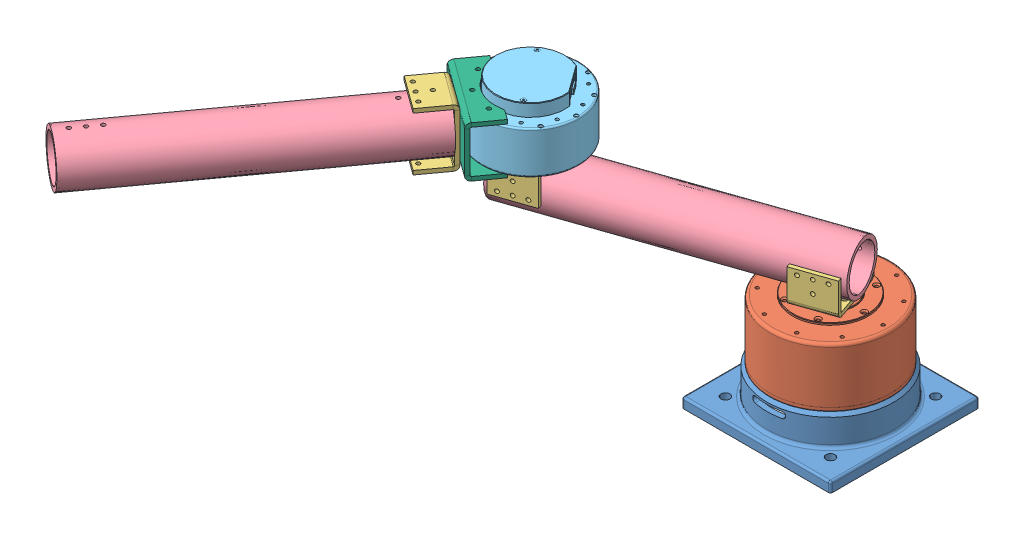
SolidWorks assembly Assembly_SCARA_P, configuration Default. Lengths in mm.
Overall size (523.57 217.6 447.44).
9 component instances, 6 part files, 25 mates.
Components (placement in the parent):
- base_link_X10-1: base_link_X10 [По умолчанию] at (81.3757 88.1097 90.3224) size (150 40 150)
- RMD-X10-S2-V3-1: RMD-X10-S2-V3 [По умолчанию] at (81.3757 180.7097 90.3224) x (0 0 -1) z (0 -1 0) size (122 122 74)
- corner_p_list__long_X10-1: corner_p_list__long_X10 [По умолчанию] at (100.7472 193.6097 83.6147) x (0.327206 0 0.944953) z (-0.944953 0 0.327206) size (58 34 41)
- tube-3: tube [По умолчанию] at (104.9995 218.6097 82.1423) x (-0.944953 0 0.327206) z (-0.327206 0 -0.944953) size (288 50 50)
- corner_p_list__long_X10-2: corner_p_list__long_X10 [По умолчанию] at (-124.1516 243.6097 161.4896) x (-0.327206 0 -0.944953) z (-0.944953 0 0.327206) size (58 34 41)
- corner_p_list__long_X10-3: corner_p_list__long_X10 [По умолчанию] at (-161.0459 271.1097 227.1652) x (0 -1 0) z (-0.808857 0 -0.588005) size (58 34 41)
- tube-4: tube [По умолчанию] at (-346.973 271.1097 448.0619) x (0.588005 0 -0.808857) z (0 -1 0) size (288 50 50)
- RMD-X8-S2-V3-1: RMD-X8-S2-V3 [По умолчанию] at (-143.5232 260.7097 168.1974) x (0.587565 0 0.809177) z (0 1 0) size (98 98 58.1)
- corner_p_list_X8-1: corner_p_list_X8 [По умолчанию] at (-205.2777 271.6097 185.12) x (0 -1 0) z (0.808857 0 0.588005) size (51 31 80)
Mates (geometry in assembly coordinates):
- Концентричный1: concentric anti-aligned: circle of First link-1; circle of RMD-X10-S2-V3-1
- Концентричный2: concentric anti-aligned: circle of First link-1; circle of RMD-X10-S2-V3-1
- Совпадение1: coincident anti-aligned: plane of First link-1 through (81.3757 128.1097 90.3224) normal (0 1 0); plane of RMD-X10-S2-V3-1 through (141.3757 128.1097 90.3224) normal (0 -1 0)
- Концентричный4: concentric anti-aligned: circle of RMD-X10-S2-V3-1; circle of corner_p_list__long_X10-1
- Совпадение3: coincident anti-aligned: plane of RMD-X10-S2-V3-1 through (81.3757 189.6097 90.3224) normal (0 1 0); plane of corner_p_list__long_X10-1 through (53.824 189.6097 73.4063) normal (0 -1 0)
- Концентричный5: concentric aligned: line of corner_p_list__long_X10-1 through (83.6986 218.6097 58.8287) axis (0.327206 0 0.944953); cylinder of tube-3 through (81.7354 218.6097 53.159) axis (0.327206 0 0.944953) radius 2
- Концентричный6: concentric aligned: cylinder of corner_p_list__long_X10-1 through (83.6986 218.6097 58.8287) axis (0.327206 0 0.944953) radius 2; cylinder of tube-3 through (81.7354 218.6097 53.159) axis (0.327206 0 0.944953) radius 2
- Концентричный7: concentric aligned: cylinder of corner_p_list__long_X10-1 through (71.8867 218.6097 62.9188) axis (0.327206 0 0.944953) radius 2; cylinder of tube-3 through (69.9235 218.6097 57.2491) axis (0.327206 0 0.944953) radius 2
- Касательность1: tangent anti-aligned: plane of corner_p_list__long_X10-1 through (70.1843 193.6097 120.654) normal (-0.327206 0 -0.944953); cylinder of tube-3 through (-167.147 218.6097 176.3775) axis (0.944953 0 -0.327206) radius 25
- Концентричный10: concentric anti-aligned: cylinder of tube-3 through (-166.7873 218.6097 139.2141) axis (0.327206 0 0.944953) radius 2; cylinder of corner_p_list__long_X10-2 through (-145.8461 218.6097 199.6911) axis (-0.327206 0 -0.944953) radius 2
- Концентричный11: concentric anti-aligned: cylinder of tube-3 through (-166.7873 218.6097 139.2141) axis (0.327206 0 0.944953) radius 2; cylinder of corner_p_list__long_X10-2 through (-145.8461 218.6097 199.6911) axis (-0.327206 0 -0.944953) radius 2
- Концентричный12: concentric anti-aligned: cylinder of tube-3 through (-154.9754 218.6097 135.124) axis (0.327206 0 0.944953) radius 2; cylinder of corner_p_list__long_X10-2 through (-134.0342 218.6097 195.601) axis (-0.327206 0 -0.944953) radius 2
- Касательность3: tangent anti-aligned: cylinder of tube-3 through (-167.147 218.6097 176.3775) axis (0.944953 0 -0.327206) radius 25; plane of corner_p_list__long_X10-2 through (-171.0749 243.6097 151.2812) normal (0.327206 0 0.944953)
- Концентричный24: concentric anti-aligned: cylinder of corner_p_list__long_X10-3 through (-184.9775 300.1097 225.2218) axis (0 -1 0) radius 2; cylinder of tube-4 through (-184.9775 236.1097 225.2218) axis (0 1 0) radius 2
- Концентричный25: concentric anti-aligned: cylinder of corner_p_list__long_X10-3 through (-184.9775 300.1097 225.2218) axis (0 -1 0) radius 2; cylinder of tube-4 through (-184.9775 236.1097 225.2218) axis (0 1 0) radius 2
- Концентричный26: concentric anti-aligned: cylinder of corner_p_list__long_X10-3 through (-192.3276 300.1097 235.3325) axis (0 -1 0) radius 2; cylinder of tube-4 through (-192.3276 236.1097 235.3325) axis (0 1 0) radius 2
- Касательность4: tangent anti-aligned: plane of corner_p_list__long_X10-3 through (-194.2091 296.1097 203.057) normal (0 -1 0); cylinder of tube-4 through (-177.6275 271.1097 215.1111) axis (-0.588005 0 0.808857) radius 25
- Концентричный27: concentric anti-aligned: circle of corner_p_list__long_X10-2; circle of RMD-X8-S2-V3-1
- Совпадение4: coincident anti-aligned: plane of corner_p_list__long_X10-2 through (-154.7146 247.6097 198.5289) normal (0 1 0); plane of RMD-X8-S2-V3-1 through (-143.5232 247.6097 168.1974) normal (0 -1 0)
- Концентричный30: concentric aligned: cylinder of RMD-X8-S2-V3-1 through (-143.5346 293.1097 210.1974) axis (0 1 0) radius 1.65; cylinder of corner_p_list_X8-1 through (-143.5346 246.1097 210.1974) axis (0 1 0) radius 2
- Концентричный31: concentric aligned: cylinder of RMD-X8-S2-V3-1 through (-168.2194 293.1097 202.1694) axis (0 1 0) radius 1.65; cylinder of corner_p_list_X8-1 through (-168.2194 246.1097 202.1694) axis (0 1 0) radius 2
- Совпадение6: coincident anti-aligned: plane of RMD-X8-S2-V3-1 through (-156.1558 293.1097 150.8001) normal (0 1 0); plane of corner_p_list_X8-1 through (-140.5692 293.1097 232.1604) normal (0 -1 0)
- Концентричный32: concentric anti-aligned: cylinder of corner_p_list__long_X10-3 through (-201.5363 284.5331 234.8197) axis (0.588005 0 -0.808857) radius 2; cylinder of corner_p_list_X8-1 through (-163.3159 284.5331 182.244) axis (-0.588005 0 0.808857) radius 2.5
- Концентричный33: concentric anti-aligned: cylinder of corner_p_list__long_X10-3 through (-188.999 284.5331 243.9338) axis (0.588005 0 -0.808857) radius 2; cylinder of corner_p_list_X8-1 through (-150.7787 284.5331 191.3581) axis (-0.588005 0 0.808857) radius 2.5
- Совпадение7: coincident anti-aligned: plane of corner_p_list__long_X10-3 through (-191.857 296.1097 199.8215) normal (0.588005 0 -0.808857); plane of corner_p_list_X8-1 through (-142.9212 293.1097 235.3958) normal (-0.588005 0 0.808857)
